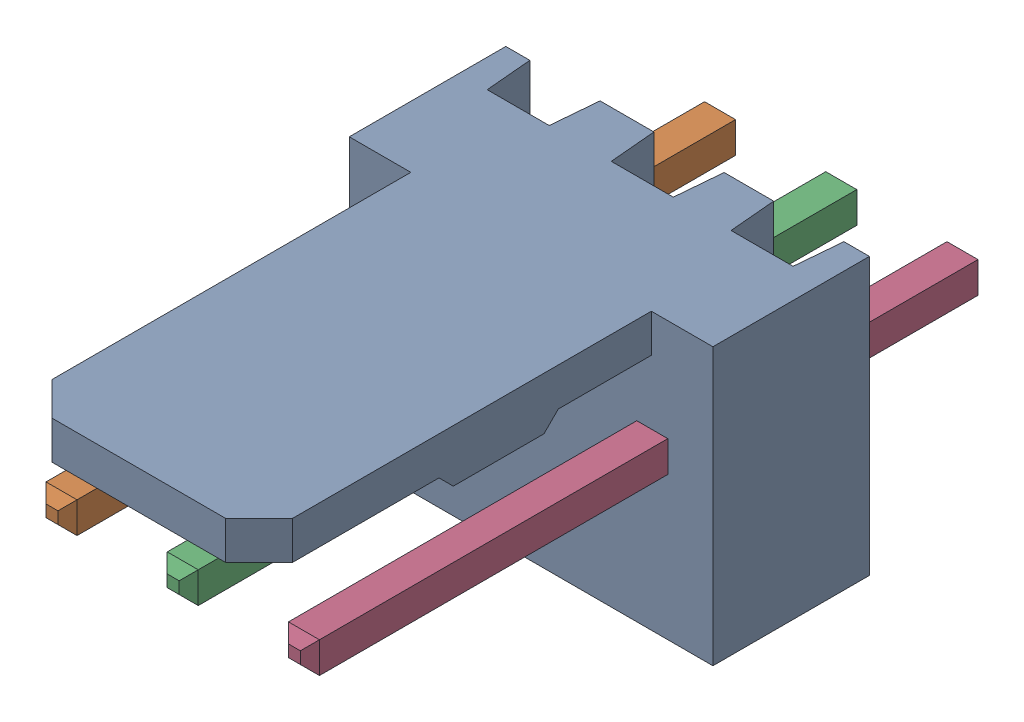
SolidWorks assembly Molex PCB 3 pin v2 v6_4, configuration Predeterminado. Lengths in mm.
Overall size (7.62 5.79 14.92).
4 component instances, 2 part files, 0 mates.
Components (placement in the parent):
- BASE9710016_2-1: BASE9710016_2 [Predeterminado] at (2.54 2.895 -8.22) size (7.62 5.79 11.5)
- PINO9710016_2-1: PINO9710016_2 [Predeterminado] at (1.27 3.325 -0.72) size (0.65 0.65 14.2)
- PINO9710016_2-2: PINO9710016_2 [Predeterminado] at (3.81 3.325 -0.72) size (0.65 0.65 14.2)
- PINO9710016_2-3: PINO9710016_2 [Predeterminado] at (6.35 3.325 -0.72) size (0.65 0.65 14.2)
